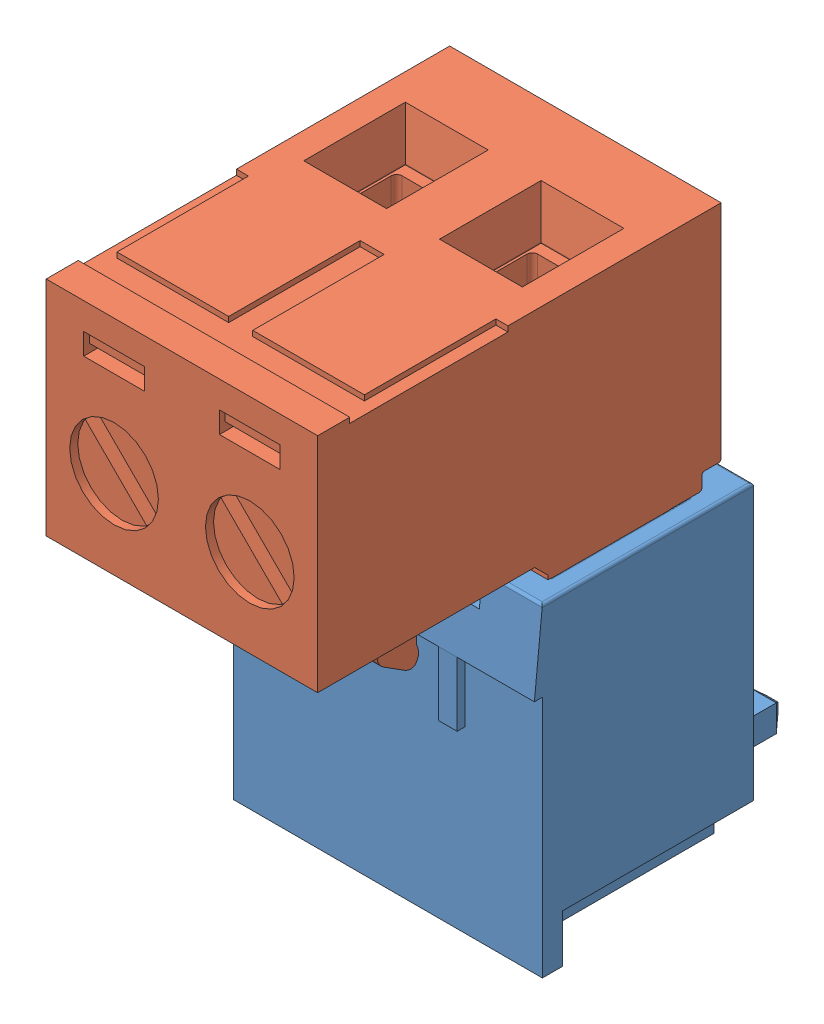
SolidWorks assembly 2EDG-5.08-02P, configuration Valor predeterminado. Lengths in mm.
Overall size (11.56 21.08 19.56).
2 component instances, 2 part files, 0 mates.
Components (placement in the parent):
- 2EDGVC-5.08-02P-1: 2EDGVC-5.08-02P [Valor predeterminado] at origin size (11.56 12.1 12.15)
- 2EGDK-5.08-02P-1: 2EGDK-5.08-02P [Valor predeterminado] at (-10.86 21.08 0.51) x (-1 0 0) z (0 0 1) size (10.16 17.33 15.1)
